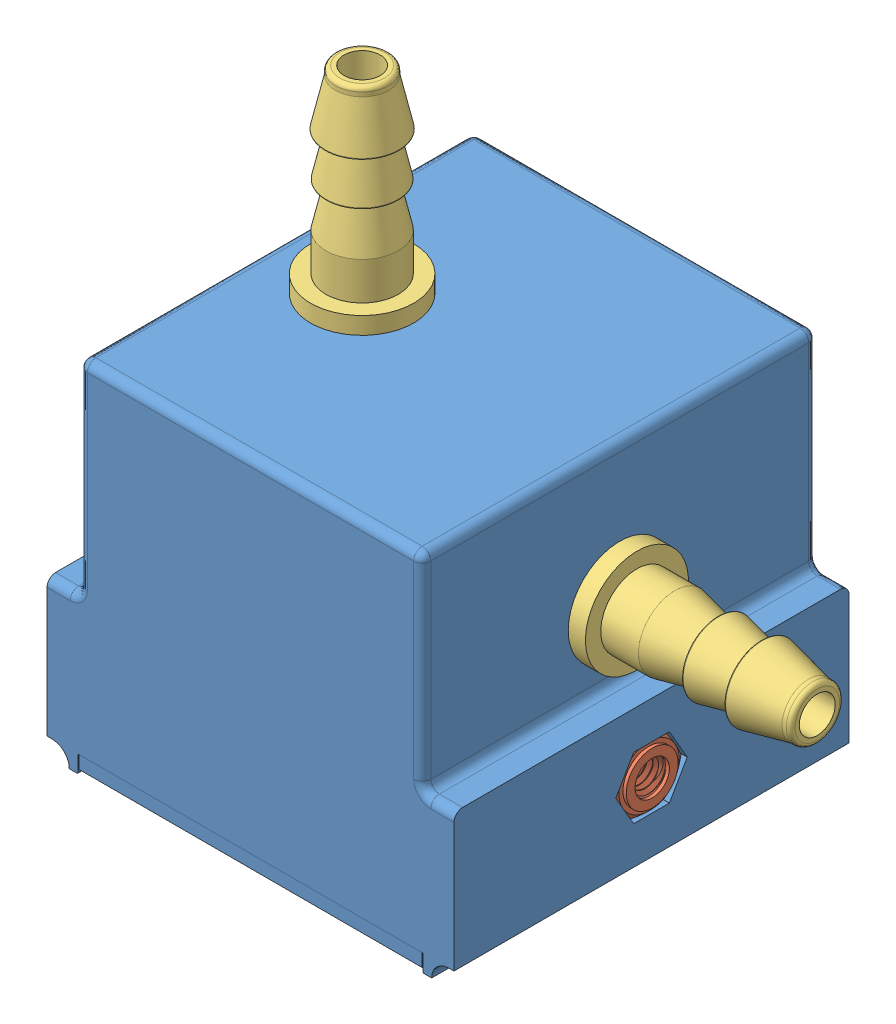
SolidWorks assembly Thermal_Block_Double_Assembly_P, configuration Default. Lengths in mm.
Overall size (66.78 65 46).
5 component instances, 3 part files, 8 mates.
Components (placement in the parent):
- Thermal_Block_Double_P-1: Thermal_Block_Double_P [Default] at (18.4797 6.8646 35.2017) size (47.4 42 46)
- M4 x 0.7 Hex Nut-1: M4 x 0.7 Hex Nut [90592A090] at (40.2797 14.8646 35.2017) x (0 -1 0) z (0 0 1) size (7 3.86 8.08)
- M4 x 0.7 Hex Nut-2: M4 x 0.7 Hex Nut [90592A090] at (-3.3203 14.8646 35.2017) x (0 1 0) z (0 0 1) size (7 3.86 8.08)
- Tube_Fitting_Final-1: Tube_Fitting_Final [Default] at (40.4797 30.8646 35.2017) x (1 0 0) z (0 0.787568 -0.616227) size (23 12 12)
- Tube_Fitting_Final-2: Tube_Fitting_Final [Default] at (8.4797 48.8646 35.2017) x (0 1 0) z (0 0 1) size (23 12 12)
Mates (geometry in assembly coordinates):
- Coincident1: coincident anti-aligned: plane of Thermal_Block_Double_P-1 through (38.6797 6.8646 35.2017) normal (1 0 0); plane of M4 x 0.7 Hex Nut-1 through (38.6797 18.3646 33.181) normal (-1 0 0)
- Concentric1: concentric aligned: circle of Thermal_Block_P-1; circle of M4 x 0.7 Hex Nut-1
- Coincident2: coincident anti-aligned: plane of Thermal_Block_Double_P-1 through (-1.7203 6.8646 35.2017) normal (-1 0 0); plane of M4 x 0.7 Hex Nut-2 through (-1.7203 11.3646 33.181) normal (1 0 0)
- Concentric2: concentric anti-aligned: circle of Thermal_Block_P-1; circle of M4 x 0.7 Hex Nut-2
- Parallel1: parallel anti-aligned: plane of Thermal_Block_Double_P-1 through (38.6797 14.8646 39.3586) normal (0 -0.5 -0.866025); plane of M4 x 0.7 Hex Nut-1 through (41.8797 18.3646 37.2224) normal (0 0.5 0.866025)
- Parallel2: parallel anti-aligned: plane of Thermal_Block_Double_P-1 through (-1.7203 18.4646 37.2801) normal (0 -1 0); plane of M4 x 0.7 Hex Nut-2 through (-4.9203 18.3646 37.2224) normal (0 1 0)
- Coincident5: coincident anti-aligned: circle of Thermal_Block_P-1; circle of Tube_Fitting_Final-1
- Coincident6: coincident anti-aligned: circle of Thermal_Block_P-1; circle of Tube_Fitting_Final-2
